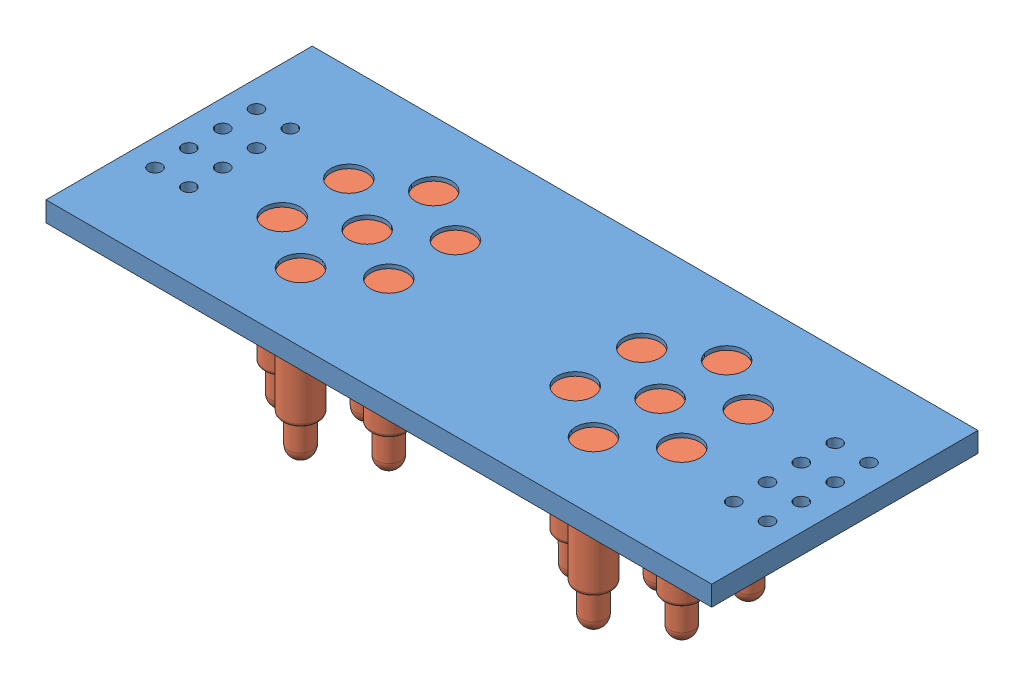
SolidWorks assembly asm_connect_brd_211223, configuration По умолчанию. Lengths in mm.
Overall size (50 12.3 20).
15 component instances, 2 part files, 28 mates.
Components (placement in the parent):
- connect_board_211223-1: connect_board_211223 [По умолчанию] at origin size (50 1.5 20)
- pogopin_a734_3_3x12_211214-1: pogopin_a734_3_3x12_211214 [По умолчанию] at (-11 -10.8 -0.1212) x (0.999781 0 0.020919) z (0 -1 0) size (3.3 3.3 12)
- pogopin_a734_3_3x12_211214-2: pogopin_a734_3_3x12_211214 [По умолчанию] at (-7 -10.8 -2.7458) x (0.999781 0 0.020919) z (0 -1 0) size (3.3 3.3 12)
- pogopin_a734_3_3x12_211214-3: pogopin_a734_3_3x12_211214 [По умолчанию] at (-15 -10.8 -2.7458) x (0.999781 0 0.020919) z (0 -1 0) size (3.3 3.3 12)
- pogopin_a734_3_3x12_211214-4: pogopin_a734_3_3x12_211214 [По умолчанию] at (-11 -10.8 -5.1212) x (0.999781 0 0.020919) z (0 -1 0) size (3.3 3.3 12)
- pogopin_a734_3_3x12_211214-5: pogopin_a734_3_3x12_211214 [По умолчанию] at (-15 -10.8 2.2542) x (0.999781 0 0.020919) z (0 -1 0) size (3.3 3.3 12)
- pogopin_a734_3_3x12_211214-6: pogopin_a734_3_3x12_211214 [По умолчанию] at (-7 -10.8 2.2542) x (0.999781 0 0.020919) z (0 -1 0) size (3.3 3.3 12)
- pogopin_a734_3_3x12_211214-7: pogopin_a734_3_3x12_211214 [По умолчанию] at (-11 -10.8 4.8788) x (0.999781 0 0.020919) z (0 -1 0) size (3.3 3.3 12)
- pogopin_a734_3_3x12_211214-8: pogopin_a734_3_3x12_211214 [По умолчанию] at (11 -10.8 -5.1212) x (0.999781 0 0.020919) z (0 -1 0) size (3.3 3.3 12)
- pogopin_a734_3_3x12_211214-9: pogopin_a734_3_3x12_211214 [По умолчанию] at (7 -10.8 -2.7458) x (0.999781 0 0.020919) z (0 -1 0) size (3.3 3.3 12)
- pogopin_a734_3_3x12_211214-10: pogopin_a734_3_3x12_211214 [По умолчанию] at (15 -10.8 -2.7458) x (0.999781 0 0.020919) z (0 -1 0) size (3.3 3.3 12)
- pogopin_a734_3_3x12_211214-11: pogopin_a734_3_3x12_211214 [По умолчанию] at (15 -10.8 2.2542) x (0.999781 0 0.020919) z (0 -1 0) size (3.3 3.3 12)
- pogopin_a734_3_3x12_211214-12: pogopin_a734_3_3x12_211214 [По умолчанию] at (7 -10.8 2.2542) x (0.999781 0 0.020919) z (0 -1 0) size (3.3 3.3 12)
- pogopin_a734_3_3x12_211214-13: pogopin_a734_3_3x12_211214 [По умолчанию] at (11 -10.8 4.8788) x (0.999781 0 0.020919) z (0 -1 0) size (3.3 3.3 12)
- pogopin_a734_3_3x12_211214-14: pogopin_a734_3_3x12_211214 [По умолчанию] at (11 -10.8 -0.1212) x (0.999781 0 0.020919) z (0 -1 0) size (3.3 3.3 12)
Mates (geometry in assembly coordinates):
- Совпадение1: coincident anti-aligned: plane of connect_board_211223-1 through (0 0 0) normal (0 -1 0); plane of pogopin_a734_3_3x12_211214-1 through (-9.3504 0 -0.0866) normal (0 1 0)
- Концентричный1: concentric anti-aligned: cylinder of connect_board_211223-1 through (-11 1.5 -0.1212) axis (0 -1 0) radius 1.35; cylinder of pogopin_a734_3_3x12_211214-1 through (-11 1.2 -0.1212) axis (0 1 0) radius 1.35
- Концентричный2: concentric anti-aligned: cylinder of connect_board_211223-1 through (-11 1.5 -5.1212) axis (0 -1 0) radius 1.35; cylinder of pogopin_a734_3_3x12_211214-4 through (-11 1.2 -5.1212) axis (0 1 0) radius 1.35
- Концентричный3: concentric anti-aligned: cylinder of connect_board_211223-1 through (-15 1.5 -2.7458) axis (0 -1 0) radius 1.35; cylinder of pogopin_a734_3_3x12_211214-3 through (-15 1.2 -2.7458) axis (0 1 0) radius 1.35
- Концентричный4: concentric anti-aligned: cylinder of connect_board_211223-1 through (-7 1.5 -2.7458) axis (0 -1 0) radius 1.35; cylinder of pogopin_a734_3_3x12_211214-2 through (-7 1.2 -2.7458) axis (0 1 0) radius 1.35
- Концентричный5: concentric anti-aligned: cylinder of connect_board_211223-1 through (-15 1.5 2.2542) axis (0 -1 0) radius 1.35; cylinder of pogopin_a734_3_3x12_211214-5 through (-15 1.2 2.2542) axis (0 1 0) radius 1.35
- Концентричный6: concentric anti-aligned: cylinder of connect_board_211223-1 through (-11 1.5 4.8788) axis (0 -1 0) radius 1.35; cylinder of pogopin_a734_3_3x12_211214-7 through (-11 1.2 4.8788) axis (0 1 0) radius 1.35
- Концентричный7: concentric anti-aligned: cylinder of connect_board_211223-1 through (-7 1.5 2.2542) axis (0 -1 0) radius 1.35; cylinder of pogopin_a734_3_3x12_211214-6 through (-7 1.2 2.2542) axis (0 1 0) radius 1.35
- Концентричный8: concentric anti-aligned: cylinder of connect_board_211223-1 through (7 1.5 -2.7458) axis (0 -1 0) radius 1.35; cylinder of pogopin_a734_3_3x12_211214-9 through (7 1.2 -2.7458) axis (0 1 0) radius 1.35
- Концентричный9: concentric anti-aligned: cylinder of connect_board_211223-1 through (11 1.5 -5.1212) axis (0 -1 0) radius 1.35; cylinder of pogopin_a734_3_3x12_211214-8 through (11 1.2 -5.1212) axis (0 1 0) radius 1.35
- Концентричный10: concentric anti-aligned: cylinder of connect_board_211223-1 through (15 1.5 -2.7458) axis (0 -1 0) radius 1.35; cylinder of pogopin_a734_3_3x12_211214-10 through (15 1.2 -2.7458) axis (0 1 0) radius 1.35
- Концентричный11: concentric anti-aligned: cylinder of connect_board_211223-1 through (11 1.5 -0.1212) axis (0 -1 0) radius 1.35; cylinder of pogopin_a734_3_3x12_211214-14 through (11 1.2 -0.1212) axis (0 1 0) radius 1.35
- Концентричный12: concentric anti-aligned: cylinder of connect_board_211223-1 through (7 1.5 2.2542) axis (0 -1 0) radius 1.35; cylinder of pogopin_a734_3_3x12_211214-12 through (7 1.2 2.2542) axis (0 1 0) radius 1.35
- Концентричный13: concentric anti-aligned: cylinder of connect_board_211223-1 through (11 1.5 4.8788) axis (0 -1 0) radius 1.35; cylinder of pogopin_a734_3_3x12_211214-13 through (11 1.2 4.8788) axis (0 1 0) radius 1.35
- Концентричный14: concentric anti-aligned: cylinder of connect_board_211223-1 through (15 1.5 2.2542) axis (0 -1 0) radius 1.35; cylinder of pogopin_a734_3_3x12_211214-11 through (15 1.2 2.2542) axis (0 1 0) radius 1.35
- Совпадение3: coincident anti-aligned: plane of pogopin_a734_3_3x12_211214-1 through (-9.6503 -3 -0.0929) normal (0 -1 0); circle of pogopin_a734_3_3x12_211214-6
- Совпадение4: coincident aligned: plane of pogopin_a734_3_3x12_211214-1 through (-9.6503 -3 -0.0929) normal (0 -1 0); plane of pogopin_a734_3_3x12_211214-7 through (-9.6503 -3 4.9071) normal (0 -1 0)
- Совпадение5: coincident aligned: plane of pogopin_a734_3_3x12_211214-1 through (-9.6503 -3 -0.0929) normal (0 -1 0); plane of pogopin_a734_3_3x12_211214-5 through (-13.6503 -3 2.2825) normal (0 -1 0)
- Совпадение6: coincident anti-aligned: plane of pogopin_a734_3_3x12_211214-1 through (-9.6503 -3 -0.0929) normal (0 -1 0); circle of pogopin_a734_3_3x12_211214-2
- Совпадение7: coincident aligned: plane of pogopin_a734_3_3x12_211214-1 through (-9.6503 -3 -0.0929) normal (0 -1 0); plane of pogopin_a734_3_3x12_211214-3 through (-13.6503 -3 -2.7175) normal (0 -1 0)
- Совпадение8: coincident aligned: plane of pogopin_a734_3_3x12_211214-1 through (-9.6503 -3 -0.0929) normal (0 -1 0); plane of pogopin_a734_3_3x12_211214-4 through (-9.6503 -3 -5.0929) normal (0 -1 0)
- Совпадение9: coincident aligned: plane of pogopin_a734_3_3x12_211214-2 through (-5.6503 -3 -2.7175) normal (0 -1 0); plane of pogopin_a734_3_3x12_211214-9 through (8.3497 -3 -2.7175) normal (0 -1 0)
- Совпадение10: coincident aligned: plane of pogopin_a734_3_3x12_211214-8 through (12.3497 -3 -5.0929) normal (0 -1 0); plane of pogopin_a734_3_3x12_211214-9 through (8.3497 -3 -2.7175) normal (0 -1 0)
- Совпадение11: coincident aligned: plane of pogopin_a734_3_3x12_211214-9 through (8.3497 -3 -2.7175) normal (0 -1 0); plane of pogopin_a734_3_3x12_211214-14 through (12.3497 -3 -0.0929) normal (0 -1 0)
- Совпадение12: coincident aligned: plane of pogopin_a734_3_3x12_211214-9 through (8.3497 -3 -2.7175) normal (0 -1 0); plane of pogopin_a734_3_3x12_211214-12 through (8.3497 -3 2.2825) normal (0 -1 0)
- Совпадение13: coincident aligned: plane of pogopin_a734_3_3x12_211214-9 through (8.3497 -3 -2.7175) normal (0 -1 0); plane of pogopin_a734_3_3x12_211214-10 through (16.3497 -3 -2.7175) normal (0 -1 0)
- Совпадение14: coincident aligned: plane of pogopin_a734_3_3x12_211214-12 through (8.3497 -3 2.2825) normal (0 -1 0); plane of pogopin_a734_3_3x12_211214-13 through (12.3497 -3 4.9071) normal (0 -1 0)
- Совпадение15: coincident aligned: plane of pogopin_a734_3_3x12_211214-11 through (16.3497 -3 2.2825) normal (0 -1 0); plane of pogopin_a734_3_3x12_211214-13 through (12.3497 -3 4.9071) normal (0 -1 0)
